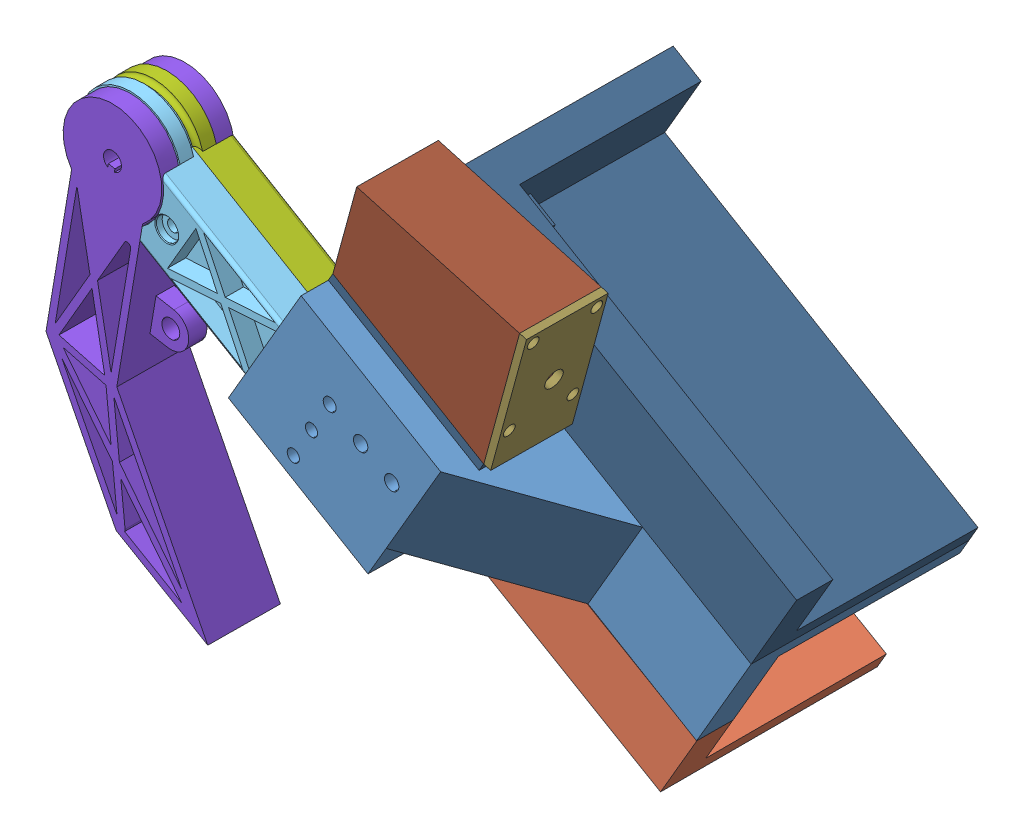
SolidWorks assembly Quarter Model, configuration Default. Lengths in mm.
Overall size (264.21 182.15 115.12).
44 component instances, 30 part files, 25 mates.
Components (placement in the parent):
- Drive Bed-1: Drive Bed [Default] at (-227.3258 208.6128 -6.3721) x (0.864152 -0.5032 0.005556) z (-0.004801 0.002796 0.999985) size (139.7 57.15 114.3)
- Battery Compartment-1: Battery Compartment [Default] at (-259.4326 153.8274 -6.0551) x (0.864166 -0.503207 0) z (0 0 1) size (139.7 31.75 76.2)
- Flat Bearing-1: Flat Bearing [Default] at (-308.0851 188.3304 -25.7534) x (-0.004801 0.002796 0.999985) z (-0.864152 0.5032 -0.005556) size (7.04 35.56 10.16)
- 393-1: 393 [Default] at (-255.2156 202.8087 -26.0901) x (-0.864152 0.5032 -0.005556) z (-0.503207 -0.864166 0) size (56.4 55.81 25)
  - SPPM206-0150BO-1: SPPM206-0150BO [Default] at (-10.5 -23.5 9.5) x (-1 0 0) z (0 0 1) size (3.3 16.36 3.3)
  - SPPM206-0150BO-2: SPPM206-0150BO [Default] at (-10.5 -23.5 -9.5) x (-1 0 0) z (0 0 1) size (3.3 16.36 3.3)
  - SPPM204-0050BO-1: SPPM204-0050BO [Default] at (0 -6.45 -6.2) size (3.3 6.41 3.3)
  - 276-2177-002 Rev1-1: 276-2177-002 Rev1 [Default] at origin size (50 27.05 25)
  - SPPM206-0150BO-3: SPPM206-0150BO [Default] at (33.5 -23.5 -9.5) x (-1 0 0) z (0 0 1) size (3.3 16.36 3.3)
  - 276-2177-008 Rev1-1: 276-2177-008 Rev1 [Default] at (25.7 -19.25 0) x (-0.086075 0 -0.996289) z (0 -1 0) size (16.7 16.7 17.5)
  - 276-2177-010 Rev1-1: 276-2177-010 Rev1 [Default] at (24.2 -4.9 0) x (0 1 0) z (0.653198 0 -0.757187) size (20.8 2 2)
  - 276-2177-001 Rev1-1: 276-2177-001 Rev1 [Default] at origin size (50 7.01 25)
  - 276-2177-012 Rev1-1: 276-2177-012 Rev1 [Default] at (25.7 -19.1 0) x (-0.525336 0 0.850895) z (0 1 0) size (6 6 2.85)
  - 276-2177-018 Rev1-1: 276-2177-018 Rev1 [Default] at (-12 2.1 0) x (0 0 -1) z (1 0 0) size (6.82 4.47 8.9)
  - 276-2177-014 Rev1-1: 276-2177-014 Rev1 [Default] at (-11.6 -15 0) x (0 1 0) z (0 0 1) size (1 18.4 20.4)
  - 276-2177-019 Rev1-1: 276-2177-019 Rev1 [Default] at (0.3 -33 0) x (-0.999228 0 0.03928) z (0.03928 0 0.999228) size (6.3 15.8 6.3)
  - SPPM206-0150BO-4: SPPM206-0150BO [Default] at (33.5 -2.5 -9.5) x (-0.585444 0 0.810713) z (-0.810713 0 -0.585444) size (3.3 16.36 3.3)
  - 276-2177-004 Rev1-1: 276-2177-004 Rev1 [Default] at (0 2.3 0) x (-0.521464 0 -0.853273) z (0 -1 0) size (5.83 5.83 4.5)
  - SPPM206-0150BO-5: SPPM206-0150BO [Default] at (33.5 -2.5 9.5) size (3.3 16.36 3.3)
  - 276-2177-019 Rev1-2: 276-2177-019 Rev1 [Default] at (13 -33 0) x (0.158525 0 -0.987355) z (-0.987355 0 -0.158525) size (6.3 15.8 6.3)
  - SPPM204-0050BO-2: SPPM204-0050BO [Default] at (0 -6.45 6.2) size (3.3 6.41 3.3)
  - FS130-FT-21100-1: FS130-FT-21100 [Default] at (0 -15 0) x (0 0 -1) z (0 1 0) size (20.4 15.4 34.7)
  - 276-2177-006 Rev1-1: 276-2177-006 Rev1 [Default] at (24.2 -0.95 0) x (-0.999044 0 -0.043716) z (0 -1 0) size (20.25 20.26 13)
  - 276-2177-009 Rev1-1: 276-2177-009 Rev1 [Default] at (15.1 -17.75 0) x (1 0 0) z (0 -1 0) size (2 2 27.5)
  - 276-2177-011 Rev1-1: 276-2177-011 Rev1 [Default] at (12.1 -0.9 0) x (0 1 0) z (-0.101873 0 0.994797) size (14.8 2 2)
  - 276-2177-007 Rev1_276-2177-007a-1: 276-2177-007 Rev1_276-2177-007a [Default] at (15.1 -10.55 0) x (0.26937 0 -0.963037) z (0 -1 0) size (14.01 14.03 13)
  - 276-2177-013 Rev1-1: 276-2177-013 Rev1 [Default] at (25.7 -31.5 0) x (-1 0 0) z (0 1 0) size (10 10 10.05)
  - SPPM206-0150BO-6: SPPM206-0150BO [Default] at (-10.5 -2.5 9.5) x (0.055695 0 -0.998448) z (0.998448 0 0.055695) size (3.3 16.36 3.3)
  - 276-2177-003 Rev1-1: 276-2177-003 Rev1 [Default] at (0 -25 0) size (48.69 26 23.69)
  - SPPM206-0150BO-7: SPPM206-0150BO [Default] at (-10.5 -2.5 -9.5) size (3.3 16.36 3.3)
  - 276-2177-005 Rev1-1: 276-2177-005 Rev1 [Default] at (12.1 2.15 0) x (-0.981818 0 0.189823) z (0 -1 0) size (19.95 19.95 7)
  - SPPM206-0150BO-8: SPPM206-0150BO [Default] at (33.5 -23.5 9.5) x (-1 0 0) z (0 0 1) size (3.3 16.36 3.3)
- HalfDogBoneAssemblyt-1: HalfDogBoneAssemblyt [Default] at (-299.7433 317.0787 -22.0023) x (0.877552 -0.479449 0.005553) z (-0.479457 -0.877565 0.000151) size (127.44 25.53 41.09)
  - HalfDogBone-1: HalfDogBone [Default] at (58.483 65.7791 105.0954) x (0.999628 0 0.027267) z (-0.027267 0 0.999628) size (124.94 12.97 36.24)
  - 36tooth gear-3: 36tooth gear [Default] at (67.4563 68.9541 103.6194) x (0 0 1) z (0 1 0) size (40.08 40.08 9.53)
  - MirrorHalfDogBone-2: MirrorHalfDogBone [Default] at (58.483 65.7791 105.0954) x (0.999628 0 0.027267) z (0.027267 0 -0.999628) size (124.94 17.47 36.24)
  - 36tooth gear-4: 36tooth gear [Default] at (67.4563 62.6041 103.6194) x (0 0 1) z (0 1 0) size (40.08 40.08 9.53)
- FrontLowerLeg-1: FrontLowerLeg [Default] at (-384.6844 171.7833 56.4764) x (-0.169494 -0.985529 0.001941) z (0.98552 -0.169482 0.005205) size (139.94 25.4 73.86)
- 12tooth gear-1: 12tooth gear [Default] at (-277.7393 215.9239 39.4036) x (0.817632 -0.575715 0.005535) z (-0.004801 0.002796 0.999985) size (14.8 14.8 7.94)
- 12tooth gear-2: 12tooth gear [Default] at (-277.7774 215.9461 47.341) x (0.817632 -0.575715 0.005535) z (-0.004801 0.002796 0.999985) size (14.8 14.8 7.94)
- Computation Bed-1: Computation Bed [Default] at (-205.8488 209.3662 -12.8452) x (0.864152 -0.5032 0.005556) z (-0.004801 0.002796 0.999985) size (147.92 61.57 104.78)
  - Computation Quarter-1: Computation Quarter [Default] at (-18.1442 -11.4585 6.574) size (139.7 31.75 104.78)
  - Solenoid Holder-1: Solenoid Holder [Default] at (-85.5408 -7.6261 73.249) x (0.965926 0.258819 0) z (0 0 1) size (59.69 47.74 28.57)
- Solenoid Cover^Quarter Model-1: Solenoid Cover^Quarter Model [Default] at (-228.8116 231.0293 60.2341) x (0.004801 -0.002796 -0.999985) z (0.964947 -0.262391 0.005366) size (28.57 47.74 2.54) (virtual)
Mates (geometry in assembly coordinates):
- Coincident9: coincident anti-aligned: plane of Drive Bed-1 through (-255.6909 203.0855 18.9076) normal (0.004801 -0.002796 -0.999985); plane of 393-1/276-2177-003 Rev1-1 through (-255.4316 202.9345 18.9092) normal (-0.004801 0.002796 0.999985)
- Concentric3: concentric anti-aligned: cylinder of Drive Bed-1 through (-255.9348 203.2275 69.7068) axis (0.004801 -0.002796 -0.999985) radius 2.54; circle of 393-1/276-2177-019 Rev1-1
- Concentric4: concentric anti-aligned: cylinder of Drive Bed-1 through (-266.9095 209.6181 69.6362) axis (0.004801 -0.002796 -0.999985) radius 2.54; cylinder of 393-1/276-2177-019 Rev1-2 through (-266.6838 209.4867 22.6369) axis (-0.004801 0.002796 0.999985) radius 1.3526
- Coincident14: coincident anti-aligned: plane of Drive Bed-1 through (-307.0419 210.943 31.3392) normal (-0.004801 0.002796 0.999985); plane of HalfDogBoneAssemblyt-1/MirrorHalfDogBone-2 through (-290.4828 193.9525 31.4662) normal (0.004801 -0.002796 -0.999985)
- Concentric5: concentric anti-aligned: cylinder of Drive Bed-1 through (-290.6657 194.059 69.5657) axis (0.004801 -0.002796 -0.999985) radius 2.159; circle of HalfDogBoneAssemblyt-1/HalfDogBone-1
- Concentric6: concentric anti-aligned: cylinder of HalfDogBoneAssemblyt-1/HalfDogBone-1 through (-367.4279 238.7579 56.372) axis (0.004801 -0.002796 -0.999985) radius 2.3813; cylinder of FrontLowerLeg-1 through (-367.3669 238.7224 43.6722) axis (-0.004801 0.002796 0.999985) radius 3.175
- Coincident15: coincident anti-aligned: plane of HalfDogBoneAssemblyt-1/MirrorHalfDogBone-2 through (-367.3364 238.7046 37.3223) normal (0.004801 -0.002796 -0.999985); plane of FrontLowerLeg-1 through (-367.3364 238.7046 37.3223) normal (-0.004801 0.002796 0.999985)
- LimitAngle1: limit planar angle = 0 rad anti-aligned: plane of FrontLowerLeg-1 through (-356.7038 224.93 43.7619) normal (0.986551 -0.163369 0.005193); plane of HalfDogBoneAssemblyt-1/HalfDogBone-1 through (-356.8768 224.0255 39.26) normal (-0.986551 0.163369 -0.005193)
- LimitAngle2: limit planar angle = 0 rad aligned: plane of HalfDogBoneAssemblyt-1/HalfDogBone-1 through (-362.7921 221.3622 56.4429) normal (-0.503207 -0.864166 0); plane of Drive Bed-1 through (-313.6156 200.0747 69.4387) normal (-0.503207 -0.864166 0)
- Coincident31: coincident anti-aligned: plane of 12tooth gear-1 through (-277.7546 215.9328 42.5786) normal (-0.004801 0.002796 0.999985); plane of 12tooth gear-2 through (-277.7546 215.9328 42.5786) normal (0.004801 -0.002796 -0.999985)
- Coincident32: coincident aligned: plane of 12tooth gear-1 through (-277.9044 214.0662 42.5831) normal (0.575722 0.817646 0.000478); plane of 12tooth gear-2 through (-277.9426 214.0884 50.5205) normal (0.575722 0.817646 0.000478)
- Coincident33: coincident aligned: plane of 12tooth gear-1 through (-275.888 215.7829 42.588) normal (-0.817632 0.575715 -0.005535); plane of 12tooth gear-2 through (-275.9261 215.8051 50.5253) normal (-0.817632 0.575715 -0.005535)
- Coincident34: coincident aligned: plane of 393-1/276-2177-008 Rev1-1 through (-277.1637 213.5691 0.7749) normal (-0.817632 0.575715 -0.005535); plane of 12tooth gear-2 through (-275.9261 215.8051 50.5253) normal (-0.817632 0.575715 -0.005535)
- Coincident35: coincident aligned: plane of 393-1/276-2177-008 Rev1-1 through (-279.8013 215.4262 0.757) normal (0.575722 0.817646 0.000478); plane of 12tooth gear-2 through (-277.9426 214.0884 50.5205) normal (0.575722 0.817646 0.000478)
- Coincident37: coincident aligned: plane of HalfDogBoneAssemblyt-1/36tooth gear-3 through (-290.5742 194.0057 50.516) normal (-0.004801 0.002796 0.999985); plane of 12tooth gear-2 through (-277.7927 215.955 50.516) normal (-0.004801 0.002796 0.999985)
- InPlace1: in place: plane of ? through (52.4052 82.2554 132.1172) normal (0.965926 0.258819 0); plane of ? through (69.4585 18.6114 0) normal (0.965926 0.258819 0); moOrthogonalPlaneRef_w of ? through (52.4052 82.2554 132.1172) normal (0.965926 0.258819 0); line of ? through (-55 69.4585 18.6114) axis (0 -0.258819 0.965926); plane of ? through (52.4052 82.2554 132.1172) normal (0.965926 0.258819 0); unknown of ?; plane of Computation Bed-1/Solenoid Holder-1 through (-228.6744 230.9494 31.6596) normal (0.964947 -0.262391 0.005366); unknown of Solenoid Cover^Quarter Model-1
- Coincident41: coincident aligned: plane of Computation Bed-1/Solenoid Holder-1; plane of Solenoid Cover^Quarter Model-1
- Coincident42: coincident aligned: moOrthogonalPlaneRef_w of Computation Bed-1/Solenoid Holder-1; plane of Solenoid Cover^Quarter Model-1
- Coincident43: coincident anti-aligned: moOrthogonalPlaneRef_w of Computation Bed-1/Solenoid Holder-1 through (-228.8116 231.0293 60.2341) axis (-0.004801 0.002796 0.999985); plane of Solenoid Cover^Quarter Model-1
- Concentric7: concentric aligned: cylinder of Drive Bed-1 through (-194.0687 152.5064 25.6949) axis (-0.503207 -0.864166 0) radius 3.175; cylinder of Battery Compartment-1 through (-194.0687 152.5064 25.6949) axis (-0.503207 -0.864166 0) radius 3.175
- Concentric8: concentric aligned: cylinder of Drive Bed-1 through (-292.8429 210.023 25.6949) axis (-0.503207 -0.864166 0) radius 3.175; cylinder of Battery Compartment-1 through (-292.8429 210.023 25.6949) axis (-0.503207 -0.864166 0) radius 3.175
- Coincident38: coincident anti-aligned: plane of Drive Bed-1 through (-243.4558 181.2647 25.6949) normal (-0.503207 -0.864166 0); plane of Battery Compartment-1 through (-243.4558 181.2647 25.6949) normal (0.503207 0.864166 0)
- Concentric9: concentric aligned: cylinder of Drive Bed-1 through (-174.899 185.4325 26.2029) axis (-0.503207 -0.864166 0) radius 3.175; cylinder of Computation Bed-1/Computation Quarter-1 through (-174.899 185.4325 26.2029) axis (-0.503207 -0.864166 0) radius 3.175
- Concentric10: concentric aligned: cylinder of Drive Bed-1 through (-278.8821 245.9824 -32.1245) axis (-0.503207 -0.864166 0) radius 3.175; cylinder of Computation Bed-1/Computation Quarter-1 through (-278.8821 245.9824 -32.1245) axis (-0.503207 -0.864166 0) radius 3.175
- Coincident39: coincident anti-aligned: plane of Drive Bed-1 through (-273.6716 242.9482 25.5679) normal (0.503207 0.864166 0); plane of Computation Bed-1/Computation Quarter-1 through (-273.6716 242.9482 25.5679) normal (-0.503207 -0.864166 0)
